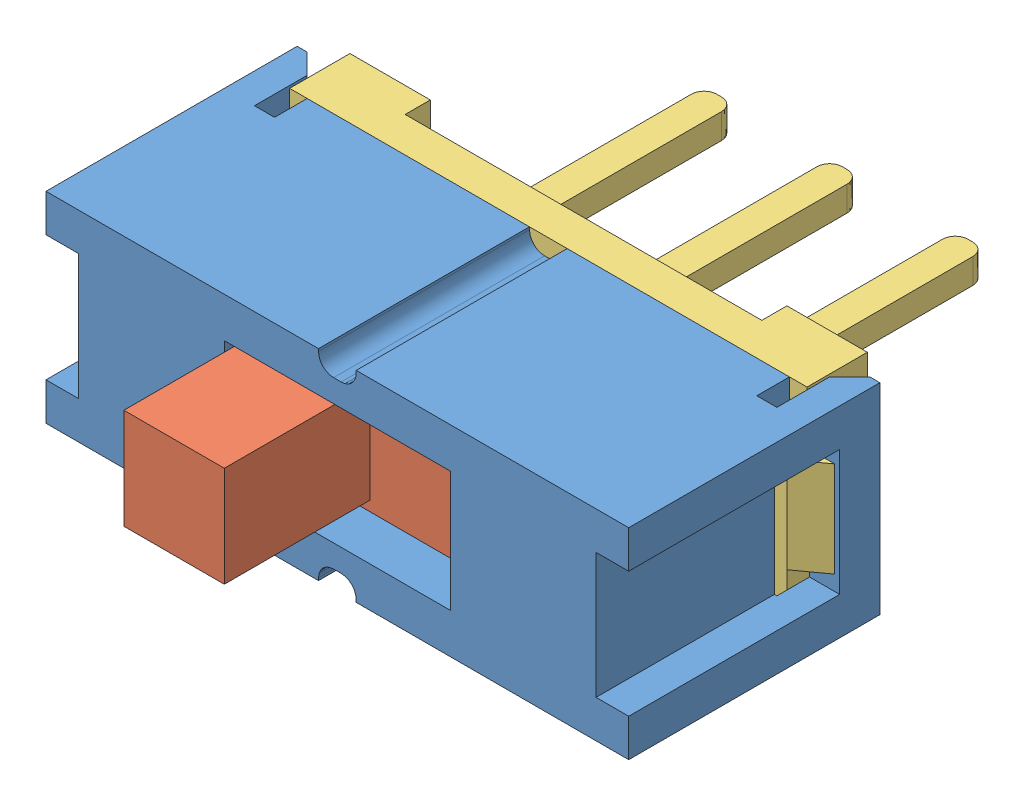
SolidWorks assembly EG1218, configuration Default. Lengths in mm.
Overall size (11.6 4 12.1).
3 component instances, 3 part files, 0 mates.
Components (placement in the parent):
- EG1218 Housing-1: EG1218 Housing [Default] at origin size (11.6 4 5)
- EG1218 Actuator-1: EG1218 Actuator [Default] at (-1.25 0 4.1) size (6.75 2.75 5.75)
- EG1218A Terminals-1: EG1218A Terminals [Default] at (0 0 -0.4) size (11.4 4 7.8)
